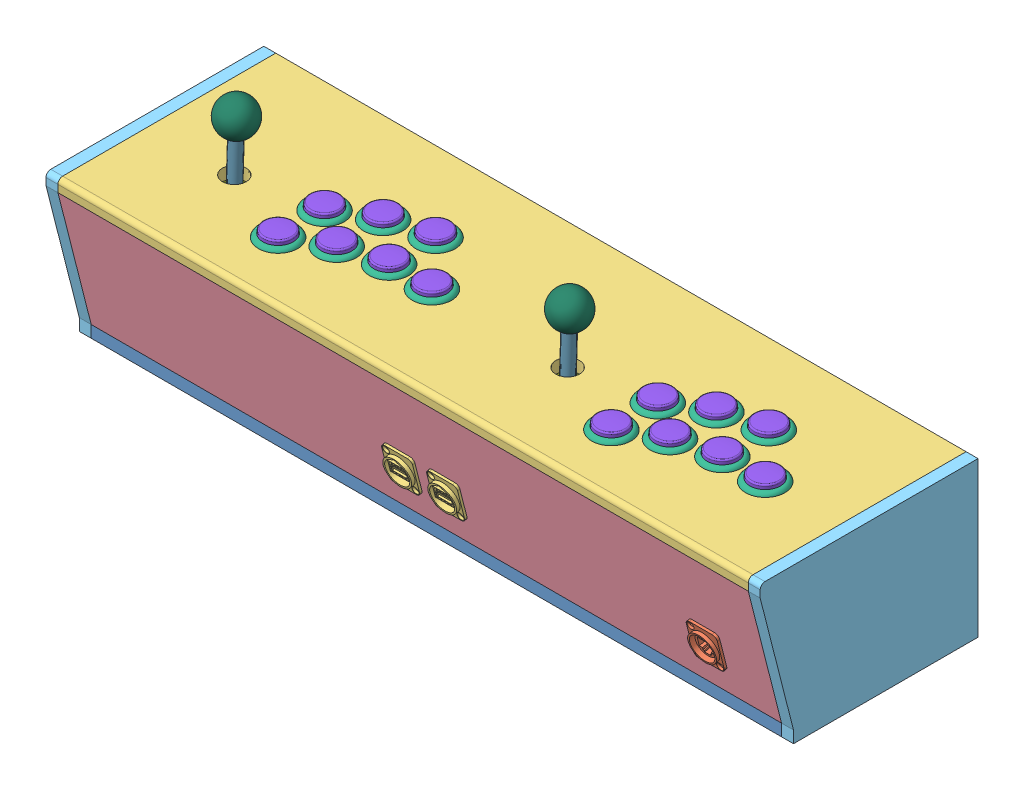
SolidWorks assembly control panel, configuration Défaut. Lengths in mm.
Overall size (600 185.9 194.8).
87 component instances, 21 part files, 64 mates.
Components (placement in the parent):
- Control panel fond-1: Control panel fond [Défaut] at (917.6057 0 155) size (580 10 155)
- control panel arriere-1: control panel arriere [Défaut] at (917.6057 10 0) size (580 110 10)
- control panel haut-1: control panel haut [Défaut] at (917.6057 130 0) x (1 0 0) z (0 -1 0) size (580 183 10)
- control panel avant-1: control panel avant [Défaut] at (917.6057 130 0) x (0 -1 0) z (-1 0 0) size (110 38 580)
- control panel cote-1: control panel cote [Défaut] at (917.6057 130 0) x (0 -1 0) z (-1 0 0) size (130 183 10)
- control panel cote-2: control panel cote [Défaut] at (1507.6057 130 0) x (0 -1 0) z (-1 0 0) size (130 183 10)
- !sanwa_button-11: !sanwa_button [Default] at (1143.0115 114.2475 107.6711) x (-0.999978 0 0.006561) z (-0.006561 0 -0.999978) size (33.02 41.99 35.3)
  - base-1: base [Default] at (-11.8549 15.7525 1.5934) size (33.02 22.1 35.3)
  - microswitch-1: microswitch [Default] at (-11.8549 -8.6795 1.5934) x (1 0 0) z (0 1 0) size (15.01 12.07 29.85)
  - top_cap-1: top_cap [Default] at (-11.8549 16.7258 1.5934) size (26.67 15.14 24.94)
- !sanwa_button-3: !sanwa_button [Default] at (1107.0115 114.2475 68.6711) x (-0.999978 0 0.006561) z (-0.006561 0 -0.999978) size (33.02 41.99 35.3)
  - base-1: base [Default] at (-11.8549 15.7525 1.5934) size (33.02 22.1 35.3)
  - microswitch-1: microswitch [Default] at (-11.8549 -8.6795 1.5934) x (1 0 0) z (0 1 0) size (15.01 12.07 29.85)
  - top_cap-1: top_cap [Default] at (-11.8549 16.7258 1.5934) size (26.67 15.14 24.94)
- !sanwa_button-5: !sanwa_button [Default] at (1040.7615 114.2475 95.6711) x (-0.999978 0 0.006561) z (-0.006561 0 -0.999978) size (33.02 41.99 35.3)
  - base-1: base [Default] at (-11.8549 15.7525 1.5934) size (33.02 22.1 35.3)
  - microswitch-1: microswitch [Default] at (-11.8549 -8.6795 1.5934) x (1 0 0) z (0 1 0) size (15.01 12.07 29.85)
  - top_cap-1: top_cap [Default] at (-11.8549 16.7258 1.5934) size (26.67 15.14 24.94)
- !sanwa_button-6: !sanwa_button [Default] at (1072.0115 114.2475 77.6711) x (-0.999978 0 0.006561) z (-0.006561 0 -0.999978) size (33.02 41.99 35.3)
  - base-1: base [Default] at (-11.8549 15.7525 1.5934) size (33.02 22.1 35.3)
  - microswitch-1: microswitch [Default] at (-11.8549 -8.6795 1.5934) x (1 0 0) z (0 1 0) size (15.01 12.07 29.85)
  - top_cap-1: top_cap [Default] at (-11.8549 16.7258 1.5934) size (26.67 15.14 24.94)
- !sanwa_button-7: !sanwa_button [Default] at (1072.0115 114.2475 116.6711) x (-0.999978 0 0.006561) z (-0.006561 0 -0.999978) size (33.02 41.99 35.3)
  - base-1: base [Default] at (-11.8549 15.7525 1.5934) size (33.02 22.1 35.3)
  - microswitch-1: microswitch [Default] at (-11.8549 -8.6795 1.5934) x (1 0 0) z (0 1 0) size (15.01 12.07 29.85)
  - top_cap-1: top_cap [Default] at (-11.8549 16.7258 1.5934) size (26.67 15.14 24.94)
- !sanwa_button-8: !sanwa_button [Default] at (1107.0115 114.2475 107.6711) x (-0.999978 0 0.006561) z (-0.006561 0 -0.999978) size (33.02 41.99 35.3)
  - base-1: base [Default] at (-11.8549 15.7525 1.5934) size (33.02 22.1 35.3)
  - microswitch-1: microswitch [Default] at (-11.8549 -8.6795 1.5934) x (1 0 0) z (0 1 0) size (15.01 12.07 29.85)
  - top_cap-1: top_cap [Default] at (-11.8549 16.7258 1.5934) size (26.67 15.14 24.94)
- !sanwa_button-9: !sanwa_button [Default] at (1040.7615 114.2475 134.6711) x (-0.999978 0 0.006561) z (-0.006561 0 -0.999978) size (33.02 41.99 35.3)
  - base-1: base [Default] at (-11.8549 15.7525 1.5934) size (33.02 22.1 35.3)
  - microswitch-1: microswitch [Default] at (-11.8549 -8.6795 1.5934) x (1 0 0) z (0 1 0) size (15.01 12.07 29.85)
  - top_cap-1: top_cap [Default] at (-11.8549 16.7258 1.5934) size (26.67 15.14 24.94)
- joystick-1: joystick [Défaut] at (988.8557 118 106) x (0 0 -1) z (0 -1 0) size (100 66.68 103.45)
  - SANWA_JOYSTICK_3-1: SANWA_JOYSTICK_3 [Défaut] at origin size (100 60 1.5)
  - SSANWA_JOYSTICK_6-1: SSANWA_JOYSTICK_6 [Défaut] at origin size (66 60 30)
  - SANWA_JOYSTICK_2-1: SANWA_JOYSTICK_2 [Défaut] x (1 0 0) z (0 1 0) size (39.99 20.68 39.98)
  - SANWA_JOYSTICK_5-1: SANWA_JOYSTICK_5 [Défaut] at (0 0 12.592) x (1 0 0) z (0 0 -1) size (66.1 66.68 17.11)
  - GT-Y-1: GT-Y [Défaut] at (0 0 27.552) size (60 60 10)
  - SANWA_JOYSTICK_0-1: SANWA_JOYSTICK_0 [Défaut] x (-0.317284 -0.947951 0.026831) z (0.943635 -0.312775 0.10828) size (10 85 10)
  - BALL-1: BALL [Défaut] at (4.8068 -3.0434 -50.6817) x (0.995532 0 0.09442) z (0.005634 0.998218 -0.059407) size (30 30 30)
  - DUSTER-1: DUSTER [Défaut] at (0 0 -2) x (-1 0 0) z (0 0 1) size (40 40 0.5)
  - E-1: E [Défaut] at (-2.9689 1.8797 31.3034) x (0.995532 0 0.09442) z (0.005634 0.998218 -0.059407) size (5.88 1.1 10)
- !sanwa_button-12: !sanwa_button [Default] at (1352.0115 114.2475 116.6711) x (-0.999978 0 0.006561) z (-0.006561 0 -0.999978) size (33.02 41.99 35.3)
  - base-1: base [Default] at (-11.8549 15.7525 1.5934) size (33.02 22.1 35.3)
  - microswitch-1: microswitch [Default] at (-11.8549 -8.6795 1.5934) x (1 0 0) z (0 1 0) size (15.01 12.07 29.85)
  - top_cap-1: top_cap [Default] at (-11.8549 16.7258 1.5934) size (26.67 15.14 24.94)
- !sanwa_button-13: !sanwa_button [Default] at (1320.7615 114.2475 95.6711) x (-0.999978 0 0.006561) z (-0.006561 0 -0.999978) size (33.02 41.99 35.3)
  - base-1: base [Default] at (-11.8549 15.7525 1.5934) size (33.02 22.1 35.3)
  - microswitch-1: microswitch [Default] at (-11.8549 -8.6795 1.5934) x (1 0 0) z (0 1 0) size (15.01 12.07 29.85)
  - top_cap-1: top_cap [Default] at (-11.8549 16.7258 1.5934) size (26.67 15.14 24.94)
- !sanwa_button-14: !sanwa_button [Default] at (1387.0115 114.2475 107.6711) x (-0.999978 0 0.006561) z (-0.006561 0 -0.999978) size (33.02 41.99 35.3)
  - base-1: base [Default] at (-11.8549 15.7525 1.5934) size (33.02 22.1 35.3)
  - microswitch-1: microswitch [Default] at (-11.8549 -8.6795 1.5934) x (1 0 0) z (0 1 0) size (15.01 12.07 29.85)
  - top_cap-1: top_cap [Default] at (-11.8549 16.7258 1.5934) size (26.67 15.14 24.94)
- !sanwa_button-16: !sanwa_button [Default] at (1387.0115 114.2475 68.6711) x (-0.999978 0 0.006561) z (-0.006561 0 -0.999978) size (33.02 41.99 35.3)
  - base-1: base [Default] at (-11.8549 15.7525 1.5934) size (33.02 22.1 35.3)
  - microswitch-1: microswitch [Default] at (-11.8549 -8.6795 1.5934) x (1 0 0) z (0 1 0) size (15.01 12.07 29.85)
  - top_cap-1: top_cap [Default] at (-11.8549 16.7258 1.5934) size (26.67 15.14 24.94)
- !sanwa_button-4: !sanwa_button [Default] at (1352.0115 114.2475 77.6711) x (-0.999978 0 0.006561) z (-0.006561 0 -0.999978) size (33.02 41.99 35.3)
  - base-1: base [Default] at (-11.8549 15.7525 1.5934) size (33.02 22.1 35.3)
  - microswitch-1: microswitch [Default] at (-11.8549 -8.6795 1.5934) x (1 0 0) z (0 1 0) size (15.01 12.07 29.85)
  - top_cap-1: top_cap [Default] at (-11.8549 16.7258 1.5934) size (26.67 15.14 24.94)
- !sanwa_button-1: !sanwa_button [Default] at (1423.0115 114.2475 107.6711) x (-0.999978 0 0.006561) z (-0.006561 0 -0.999978) size (33.02 41.99 35.3)
  - base-1: base [Default] at (-11.8549 15.7525 1.5934) size (33.02 22.1 35.3)
  - microswitch-1: microswitch [Default] at (-11.8549 -8.6795 1.5934) x (1 0 0) z (0 1 0) size (15.01 12.07 29.85)
  - top_cap-1: top_cap [Default] at (-11.8549 16.7258 1.5934) size (26.67 15.14 24.94)
- !sanwa_button-2: !sanwa_button [Default] at (1320.7615 114.2475 134.6711) x (-0.999978 0 0.006561) z (-0.006561 0 -0.999978) size (33.02 41.99 35.3)
  - base-1: base [Default] at (-11.8549 15.7525 1.5934) size (33.02 22.1 35.3)
  - microswitch-1: microswitch [Default] at (-11.8549 -8.6795 1.5934) x (1 0 0) z (0 1 0) size (15.01 12.07 29.85)
  - top_cap-1: top_cap [Default] at (-11.8549 16.7258 1.5934) size (26.67 15.14 24.94)
- joystick-2: joystick [Défaut] at (1268.8557 118 106) x (0 0 -1) z (0 -1 0) size (100 66.68 103.45)
  - SANWA_JOYSTICK_3-1: SANWA_JOYSTICK_3 [Défaut] at origin size (100 60 1.5)
  - SSANWA_JOYSTICK_6-1: SSANWA_JOYSTICK_6 [Défaut] at origin size (66 60 30)
  - SANWA_JOYSTICK_2-1: SANWA_JOYSTICK_2 [Défaut] x (1 0 0) z (0 1 0) size (39.99 20.68 39.98)
  - SANWA_JOYSTICK_5-1: SANWA_JOYSTICK_5 [Défaut] at (0 0 12.592) x (1 0 0) z (0 0 -1) size (66.1 66.68 17.11)
  - GT-Y-1: GT-Y [Défaut] at (0 0 27.552) size (60 60 10)
  - SANWA_JOYSTICK_0-1: SANWA_JOYSTICK_0 [Défaut] x (-0.317284 -0.947951 0.026831) z (0.943635 -0.312775 0.10828) size (10 85 10)
  - BALL-1: BALL [Défaut] at (4.8068 -3.0434 -50.6817) x (0.995532 0 0.09442) z (0.005634 0.998218 -0.059407) size (30 30 30)
  - DUSTER-1: DUSTER [Défaut] at (0 0 -2) x (-1 0 0) z (0 0 1) size (40 40 0.5)
  - E-1: E [Défaut] at (-2.9689 1.8797 31.3034) x (0.995532 0 0.09442) z (0.005634 0.998218 -0.059407) size (5.88 1.1 10)
- prise hdmi-1: prise hdmi [Défaut] at (1378.6057 44.5 0) x (-1 0 0) z (0 0 -1) size (26 31 40.7)
- prise jack-1: prise jack [Défaut] at (1424.6057 45.5 0) x (-1 0 0) z (0 0 -1) size (26 35 37.11)
- prise rj45-1: prise rj45 [Défaut] at (1444.6057 45.0594 166.0912) x (-1 0 0) z (0 0.246679 -0.969097) size (26 31 44.9)
- prise usb-1: prise usb [Défaut] at (1226.3516 45.5775 164.0561) x (1 0 0) z (0 -0.246679 0.969097) size (26 31 40.55)
- prise usb-2: prise usb [Défaut] at (1188.5526 45.5775 164.0561) x (1 0 0) z (0 -0.246679 0.969097) size (26 31 40.55)
Mates (geometry in assembly coordinates):
- Coïncidente1: coincident anti-aligned: line of Control panel fond-1 through (1497.6057 10 0) axis (-1 0 0); line of control panel arriere-1 through (917.6057 10 0) axis (1 0 0)
- Coïncidente2: coincident aligned: plane of Control panel fond-1 through (917.6057 10 155) normal (-1 0 0); plane of control panel arriere-1 through (917.6057 10 10) normal (-1 0 0)
- Coïncidente3: coincident anti-aligned: line of control panel arriere-1 through (1497.6057 120 0) axis (-1 0 0); line of control panel haut-1 through (917.6057 120 0) axis (1 0 0)
- Coïncidente4: coincident anti-aligned: plane of control panel arriere-1 through (917.6057 120 10) normal (0 1 0); plane of control panel haut-1 through (917.6057 120 0) normal (0 -1 0)
- Coïncidente5: coincident anti-aligned: plane of Control panel fond-1 through (917.6057 10 155) normal (0 1 0); plane of control panel arriere-1 through (917.6057 10 10) normal (0 -1 0)
- Coïncidente6: coincident aligned: plane of control panel arriere-1 through (917.6057 10 10) normal (-1 0 0); plane of control panel haut-1 through (917.6057 120 0) normal (-1 0 0)
- Sur place1: in place: plane of ? through (-392.1437 83.6586 -77.5) normal (-1 0 0); plane of ? through (-392.1437 0 0) normal (-1 0 0); moOrthogonalPlaneRef_w of ? through (-392.1437 83.6586 -77.5) normal (-1 0 0); line of ? through (-55 -392.1437 0) axis (0 0 1); plane of ? through (-392.1437 83.6586 -77.5) normal (-1 0 0); plane of ? through (-392.1437 0 0) normal (0 0 1); plane of control panel haut-1 through (917.6057 120 0) normal (-1 0 0); unknown of ?
- Coïncidente7: coincident aligned: plane of control panel haut-1; plane of control panel avant-1
- Coïncidente8: coincident aligned: moOrthogonalPlaneRef_w of control panel haut-1 through (917.6057 130 0) normal (0 0 1); plane of control panel avant-1
- Coïncidente9: coincident anti-aligned: moOrthogonalPlaneRef_w of control panel haut-1 through (917.6057 130 0) normal (0 1 0); plane of control panel avant-1
- Sur place2: in place: plane of ? through (-392.1437 83.6586 -77.5) normal (-1 0 0); plane of ? through (-392.1437 0 0) normal (-1 0 0); plane of ? through (-392.1437 83.6586 -77.5) normal (-1 0 0); line of ? through (-55 -392.1437 0) axis (0 0 1); plane of ? through (-392.1437 83.6586 -77.5) normal (-1 0 0); plane of ? through (-392.1437 0 0) normal (0 0 1); plane of control panel haut-1 through (917.6057 120 0) normal (-1 0 0); unknown of ?
- Coïncidente10: coincident aligned: plane of control panel haut-1; plane of control panel cote-1
- Coïncidente11: coincident aligned: moOrthogonalPlaneRef_w of control panel haut-1 through (917.6057 130 0) normal (0 0 1); plane of control panel cote-1
- Coïncidente12: coincident anti-aligned: moOrthogonalPlaneRef_w of control panel haut-1 through (917.6057 130 0) normal (0 1 0); plane of control panel cote-1
- Coaxiale1: concentric aligned: cylinder of control panel haut-1 through (1052.6057 120 133) axis (0 1 0) radius 14; cylinder of !sanwa_button-9/base-1 through (1052.6057 133 133) axis (0 1 0) radius 14.732
- Coïncidente19: coincident anti-aligned: plane of control panel haut-1 through (917.6057 130 0) normal (0 1 0); plane of !sanwa_button-9/base-1 through (1037.874 130 133.0967) normal (0 -1 0)
- Coaxiale2: concentric aligned: cylinder of control panel haut-1 through (1052.6057 120 94) axis (0 1 0) radius 14; cylinder of !sanwa_button-5/base-1 through (1052.6057 133 94) axis (0 1 0) radius 14.732
- Coïncidente20: coincident anti-aligned: plane of control panel haut-1 through (917.6057 130 0) normal (0 1 0); plane of !sanwa_button-5/base-1 through (1037.874 130 94.0967) normal (0 -1 0)
- Coaxiale3: concentric aligned: cylinder of control panel haut-1 through (1083.8557 120 76) axis (0 1 0) radius 14; cylinder of !sanwa_button-6/base-1 through (1083.8557 133 76) axis (0 1 0) radius 14.732
- Coaxiale4: concentric aligned: cylinder of control panel haut-1 through (1083.8557 120 115) axis (0 1 0) radius 14; cylinder of !sanwa_button-7/base-1 through (1083.8557 133 115) axis (0 1 0) radius 14.732
- Coaxiale5: concentric aligned: cylinder of control panel haut-1 through (1118.8557 120 67) axis (0 1 0) radius 14; cylinder of !sanwa_button-3/base-1 through (1118.8557 133 67) axis (0 1 0) radius 14.732
- Coaxiale6: concentric aligned: cylinder of control panel haut-1 through (1118.8557 120 106) axis (0 1 0) radius 14; cylinder of !sanwa_button-8/base-1 through (1118.8557 133 106) axis (0 1 0) radius 14.732
- Coïncidente21: coincident anti-aligned: plane of control panel haut-1 through (917.6057 130 0) normal (0 1 0); plane of !sanwa_button-7/base-1 through (1069.124 130 115.0967) normal (0 -1 0)
- Coïncidente22: coincident anti-aligned: plane of control panel haut-1 through (917.6057 130 0) normal (0 1 0); plane of !sanwa_button-6/base-1 through (1069.124 130 76.0967) normal (0 -1 0)
- Coïncidente24: coincident anti-aligned: plane of control panel haut-1 through (917.6057 130 0) normal (0 1 0); plane of !sanwa_button-8/base-1 through (1104.124 130 106.0967) normal (0 -1 0)
- Coïncidente25: coincident anti-aligned: plane of control panel haut-1 through (917.6057 130 0) normal (0 1 0); plane of !sanwa_button-3/base-1 through (1104.124 130 67.0967) normal (0 -1 0)
- Coaxiale8: concentric aligned: cylinder of control panel haut-1 through (1154.8557 120 106) axis (0 1 0) radius 14; cylinder of !sanwa_button-11/base-1 through (1154.8557 133 106) axis (0 1 0) radius 14.732
- Coïncidente26: coincident anti-aligned: plane of control panel haut-1 through (917.6057 130 0) normal (0 1 0); plane of !sanwa_button-11/base-1 through (1140.124 130 106.0967) normal (0 -1 0)
- Coaxiale9: concentric aligned: cylinder of control panel haut-1 through (1332.6057 120 94) axis (0 1 0) radius 14; cylinder of !sanwa_button-13/base-1 through (1332.6057 133 94) axis (0 1 0) radius 14.732
- Coaxiale10: concentric aligned: cylinder of control panel haut-1 through (1332.6057 120 133) axis (0 1 0) radius 14; cylinder of !sanwa_button-2/base-1 through (1332.6057 133 133) axis (0 1 0) radius 14.732
- Coaxiale11: concentric aligned: cylinder of control panel haut-1 through (1363.8557 120 76) axis (0 1 0) radius 14; cylinder of !sanwa_button-4/base-1 through (1363.8557 133 76) axis (0 1 0) radius 14.732
- Coaxiale12: concentric aligned: cylinder of control panel haut-1 through (1363.8557 120 115) axis (0 1 0) radius 14; cylinder of !sanwa_button-12/base-1 through (1363.8557 133 115) axis (0 1 0) radius 14.732
- Coaxiale13: concentric aligned: cylinder of control panel haut-1 through (1398.8557 120 67) axis (0 1 0) radius 14; cylinder of !sanwa_button-16/base-1 through (1398.8557 133 67) axis (0 1 0) radius 14.732
- Coaxiale14: concentric aligned: cylinder of control panel haut-1 through (1398.8557 120 106) axis (0 1 0) radius 14; cylinder of !sanwa_button-14/base-1 through (1398.8557 133 106) axis (0 1 0) radius 14.732
- Coaxiale16: concentric aligned: cylinder of control panel haut-1 through (1434.8557 120 106) axis (0 1 0) radius 14; cylinder of !sanwa_button-1/base-1 through (1434.8557 133 106) axis (0 1 0) radius 14.732
- Coïncidente28: coincident anti-aligned: plane of control panel haut-1 through (917.6057 130 0) normal (0 1 0); plane of !sanwa_button-13/base-1 through (1317.874 130 94.0967) normal (0 -1 0)
- Coïncidente29: coincident anti-aligned: plane of control panel haut-1 through (917.6057 130 0) normal (0 1 0); plane of !sanwa_button-2/base-1 through (1317.874 130 133.0967) normal (0 -1 0)
- Coïncidente30: coincident anti-aligned: plane of control panel haut-1 through (917.6057 130 0) normal (0 1 0); plane of !sanwa_button-4/base-1 through (1349.124 130 76.0967) normal (0 -1 0)
- Coïncidente31: coincident anti-aligned: plane of control panel haut-1 through (917.6057 130 0) normal (0 1 0); plane of !sanwa_button-14/base-1 through (1384.124 130 106.0967) normal (0 -1 0)
- Coïncidente32: coincident anti-aligned: plane of control panel haut-1 through (917.6057 130 0) normal (0 1 0); plane of !sanwa_button-12/base-1 through (1349.124 130 115.0967) normal (0 -1 0)
- Coïncidente33: coincident anti-aligned: plane of control panel haut-1 through (917.6057 130 0) normal (0 1 0); plane of !sanwa_button-16/base-1 through (1384.124 130 67.0967) normal (0 -1 0)
- Coïncidente34: coincident anti-aligned: plane of control panel haut-1 through (917.6057 130 0) normal (0 1 0); plane of !sanwa_button-1/base-1 through (1420.124 130 106.0967) normal (0 -1 0)
- Coïncidente36: coincident anti-aligned: plane of control panel haut-1 through (917.6057 120 0) normal (0 -1 0); plane of joystick-1/DUSTER-1 through (988.8557 120 106) normal (0 1 0)
- Coaxiale19: concentric anti-aligned: cylinder of control panel haut-1 through (988.8557 120 106) axis (0 1 0) radius 10; circle of joystick-1/DUSTER-1
- Parallèle1: parallel aligned: plane of control panel cote-1 through (907.6057 130 0) normal (-1 0 0); plane of joystick-1/SANWA_JOYSTICK_3-1 through (958.8557 118 151) normal (-1 0 0)
- Coïncidente38: coincident anti-aligned: plane of control panel haut-1 through (917.6057 120 0) normal (0 -1 0); plane of joystick-2/DUSTER-1 through (1268.8557 120 106) normal (0 1 0)
- Coaxiale20: concentric anti-aligned: cylinder of control panel haut-1 through (1268.8557 120 106) axis (0 1 0) radius 10; circle of joystick-2/DUSTER-1
- Parallèle2: parallel anti-aligned: plane of control panel cote-2 through (1507.6057 130 0) normal (1 0 0); plane of joystick-2/SANWA_JOYSTICK_3-1 through (1238.8557 118 151) normal (-1 0 0)
- Coïncidente40: coincident anti-aligned: line of control panel haut-1 through (1497.6057 130 0) axis (0 0 1); line of control panel cote-2 through (1497.6057 130 179) axis (0 0 -1)
- Coïncidente41: coincident anti-aligned: plane of control panel arriere-1 through (1497.6057 10 10) normal (1 0 0); plane of control panel cote-2 through (1497.6057 130 0) normal (-1 0 0)
- Coïncidente42: coincident anti-aligned: line of control panel arriere-1 through (1497.6057 10 0) axis (0 1 0); line of control panel cote-2 through (1497.6057 130 0) axis (0 -1 0)
- Coïncidente44: coincident anti-aligned: plane of control panel arriere-1 through (917.6057 10 0) normal (0 0 -1); plane of prise hdmi-1 through (1378.6057 44.5 0) normal (0 0 1)
- Distance1: distance = 70 mm aligned: plane of prise hdmi-1 through (1378.6057 60 0) normal (0 1 0); plane of control panel haut-1 through (917.6057 130 0) normal (0 1 0)
- Coïncidente54: coincident aligned: plane of prise usb-1 through (1226.3516 45.5775 164.0561) normal (0 0.246679 -0.969097); plane of prise usb-2 through (1188.5526 45.5775 164.0561) normal (0 0.246679 -0.969097)
- Coïncidente55: coincident anti-aligned: plane of control panel avant-1 through (1497.6057 10 155) normal (0 -0.246679 0.969097); plane of prise usb-2 through (1188.5526 45.5775 164.0561) normal (0 0.246679 -0.969097)
- Coïncidente56: coincident aligned: plane of prise usb-1 through (1226.3516 60.5985 167.8796) normal (0 0.969097 0.246679); plane of prise usb-2 through (1188.5526 60.5985 167.8796) normal (0 0.969097 0.246679)
- Distance6: distance = 70 mm: line of control panel haut-1 through (917.6057 130 179) axis (1 0 0); plane of prise usb-2 through (1188.5526 60.5985 167.8796) normal (0 0.969097 0.246679)
- Coïncidente57: coincident anti-aligned: plane of control panel arriere-1 through (917.6057 10 0) normal (0 0 -1); plane of prise jack-1 through (1424.6057 45.5 0) normal (0 0 1)
- Distance7: distance = 30 mm aligned: plane of prise jack-1 through (1424.6057 30 0) normal (0 -1 0); plane of Control panel fond-1 through (917.6057 0 155) normal (0 -1 0)
- Coïncidente59: coincident anti-aligned: plane of control panel avant-1 through (1497.6057 10 155) normal (0 -0.246679 0.969097); plane of prise rj45-1 through (1444.6057 45.5775 164.0561) normal (0 0.246679 -0.969097)
- Coïncidente60: coincident aligned: plane of prise rj45-1 through (1431.6057 30.5565 160.2326) normal (0 -0.969097 -0.246679); plane of prise usb-1 through (1226.3516 30.5565 160.2326) normal (0 -0.969097 -0.246679)
- Distance8: distance = 40 mm: plane of prise rj45-1 through (1457.6057 30.5565 160.2326) normal (1 0 0); line of control panel avant-1 through (1497.6057 10 155) axis (0 0.969097 0.246679)
- Distance9: distance = 20 mm anti-aligned: plane of prise jack-1 through (1411.6057 61 -4.5) normal (-1 0 0); plane of prise hdmi-1 through (1391.6057 29 -2) normal (1 0 0)
- Distance10: distance = 70 mm aligned: plane of control panel cote-2 through (1507.6057 130 0) normal (1 0 0); plane of prise jack-1 through (1437.6057 45.5 0) normal (1 0 0)
